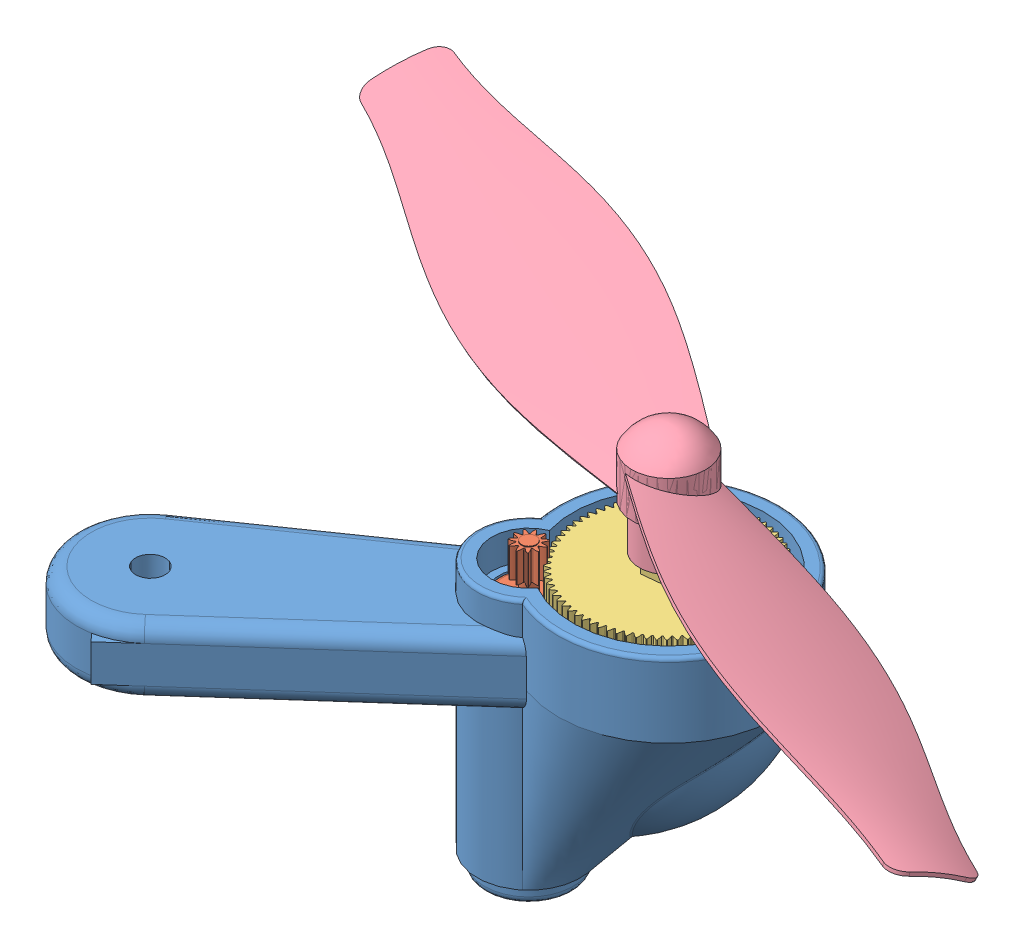
SolidWorks assembly Assem1, configuration Default. Lengths in mm.
Overall size (139.3 53.5 87.1).
4 component instances, 4 part files, 9 mates.
Components (placement in the parent):
- Part3-2: Part3 [Default] at (231.4789 76.8065 172.5633) x (0.785639 0 -0.618685) z (0.618685 0 0.785639) size (75.23 36.54 30.33)
- Part5-2: Part5 [Default] at (220.8728 62.8065 180.9156) x (0.74626 0 -0.665655) z (0.665655 0 0.74626) size (8 26.1 8)
- Part4-3: Part4 [Default] at (231.4789 66.8065 172.5633) x (-0.585794 0 -0.81046) z (0.81046 0 -0.585794) size (24 29 23.99)
- Part2-1: Part2 [Default] at (231.4789 88.8065 172.5633) x (-0.408982 0 0.912542) z (-0.912542 0 -0.408982) size (18.79 15 144.23)
Mates (geometry in assembly coordinates):
- Coincident1: coincident aligned: plane of Part3-2 through (226.1759 82.8065 176.7395) normal (0 1 0); plane of Part5-2 through (223.8578 82.8065 178.253) normal (0 1 0)
- Concentric1: concentric anti-aligned: cylinder of Part3-2 through (220.8728 60.8065 180.9156) axis (0 1 0) radius 4; cylinder of Part5-2 through (220.8728 62.8065 180.9156) axis (0 -1 0) radius 4
- Coincident2: coincident anti-aligned: plane of Part3-2 through (231.4789 66.8065 172.5633) normal (0 1 0); plane of Part4-3 through (231.4789 66.8065 172.5633) normal (0 -1 0)
- Concentric2: concentric anti-aligned: cylinder of Part3-2 through (231.4789 66.8065 172.5633) axis (0 1 0) radius 3; cylinder of Part4-3 through (231.4789 66.8065 172.5633) axis (0 -1 0) radius 3
- GearMate5: gear = 750 : 110 mm: cylinder of Part5-2 through (220.8728 62.8065 180.9156) axis (0 -1 0) radius 4; cylinder of Part4-3 through (231.4789 66.8065 172.5633) axis (0 -1 0) radius 3
- Concentric4: concentric aligned: cylinder of Part4-3 through (231.4789 66.8065 172.5633) axis (0 -1 0) radius 3; cylinder of Part2-1 through (231.4789 88.8065 172.5633) axis (0 -1 0) radius 4
- Coincident9: coincident anti-aligned: plane of Part4-3 through (232.6596 86.8065 169.9291) normal (-0.102082 0 -0.994776); plane of Part2-1 through (229.7879 95.8065 170.2237) normal (0.102082 0 0.994776)
- Coincident10: coincident anti-aligned: plane of Part4-3 through (234.3506 86.8065 172.2687) normal (0.81046 0 -0.585794); plane of Part2-1 through (232.6596 95.8065 169.9291) normal (-0.81046 0 0.585794)
- Coincident11: coincident anti-aligned: plane of Part4-3 through (229.7215 95.8065 170.132) normal (0 1 0); plane of Part2-1 through (231.4789 95.8065 172.5633) normal (0 -1 0)
